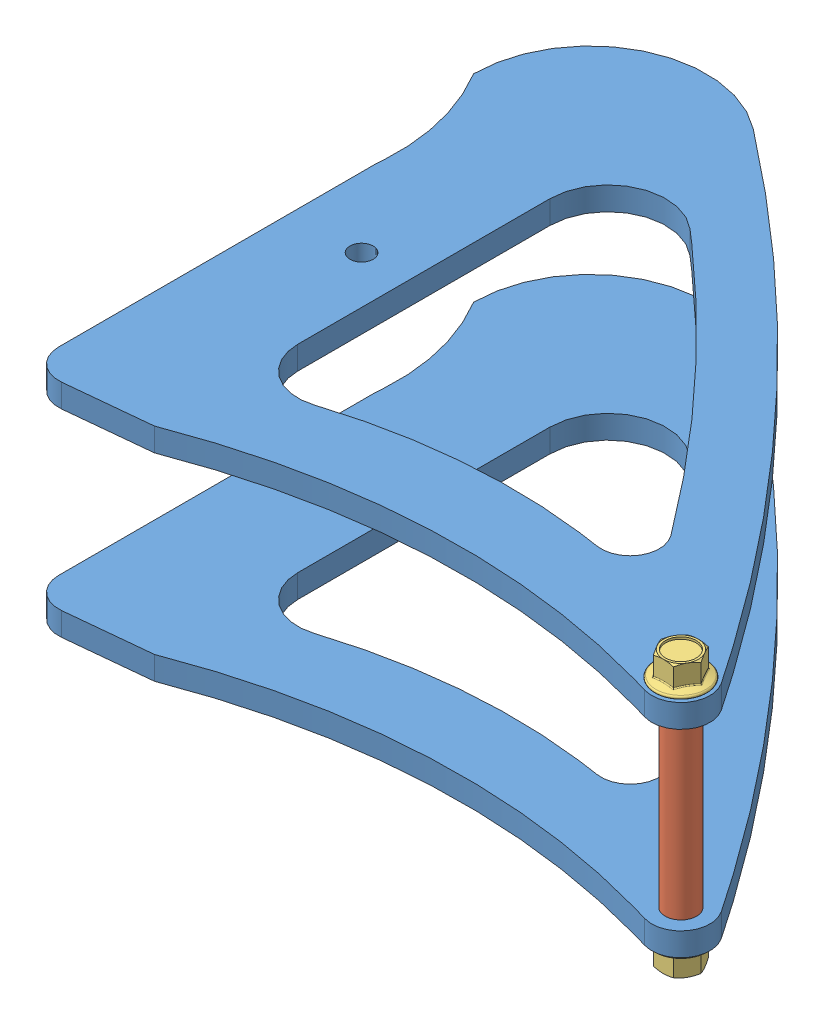
SolidWorks assembly landing, configuration Default. Lengths in mm.
Overall size (56.44 23.4 50.68).
5 component instances, 3 part files, 8 mates.
Components (placement in the parent):
- landi-1: landi [Default] at (-50.7056 4.6538 33.6243) size (56.44 2 50.68)
- metal-spacer-for-landing-1: metal-spacer-for-landing [Default] at (3.2364 21.6538 28.817) x (1 0 0) z (0 -1 0) size (2.7 2.7 15)
- landi-2: landi [Default] at (-50.7056 21.6538 33.6243) size (56.44 2 50.68)
- hex flange machine screw_am-2: hex flange machine screw_am [B18.6.7M - M2 x 0.4 x 4 Indented HFMS --4N] at (3.2364 25.8538 28.817) x (0 -1 0) z (0 0 1) size (6.2 4.5 4.5)
- hex flange machine screw_am-3: hex flange machine screw_am [B18.6.7M - M2 x 0.4 x 4 Indented HFMS --4N] at (3.2364 2.4538 28.817) x (0 1 0) z (0 0 1) size (6.2 4.5 4.5)
Mates (geometry in assembly coordinates):
- Concentric1: concentric anti-aligned: circle of landi-1; circle of metal-spacer-for-landing-1
- Coincident1: coincident anti-aligned: plane of landi-1 through (-50.7056 6.6538 33.6243) normal (0 1 0); plane of metal-spacer-for-landing-1 through (3.2364 6.6538 28.817) normal (0 -1 0)
- Concentric2: concentric anti-aligned: circle of metal-spacer-for-landing-1; circle of landi-2
- Coincident2: coincident anti-aligned: plane of metal-spacer-for-landing-1 through (3.2364 21.6538 28.817) normal (0 1 0); plane of landi-2 through (-50.7056 21.6538 33.6243) normal (0 -1 0)
- Concentric3: concentric aligned: cylinder of landi-2 through (3.2364 21.6538 28.817) axis (0 1 0) radius 1; cylinder of hex flange machine screw_am-2 through (3.2364 51.2538 28.817) axis (0 1 0) radius 1
- Coincident3: coincident anti-aligned: plane of landi-2 through (-50.7056 23.6538 33.6243) normal (0 1 0); plane of hex flange machine screw_am-2 through (4.2364 23.6538 28.817) normal (0 -1 0)
- Concentric4: concentric anti-aligned: cylinder of landi-1 through (3.2364 4.6538 28.817) axis (0 1 0) radius 1; cylinder of hex flange machine screw_am-3 through (3.2364 -22.9462 28.817) axis (0 -1 0) radius 1
- Coincident4: coincident anti-aligned: plane of landi-1 through (-50.7056 4.6538 33.6243) normal (0 -1 0); plane of hex flange machine screw_am-3 through (2.2364 4.6538 28.817) normal (0 1 0)
